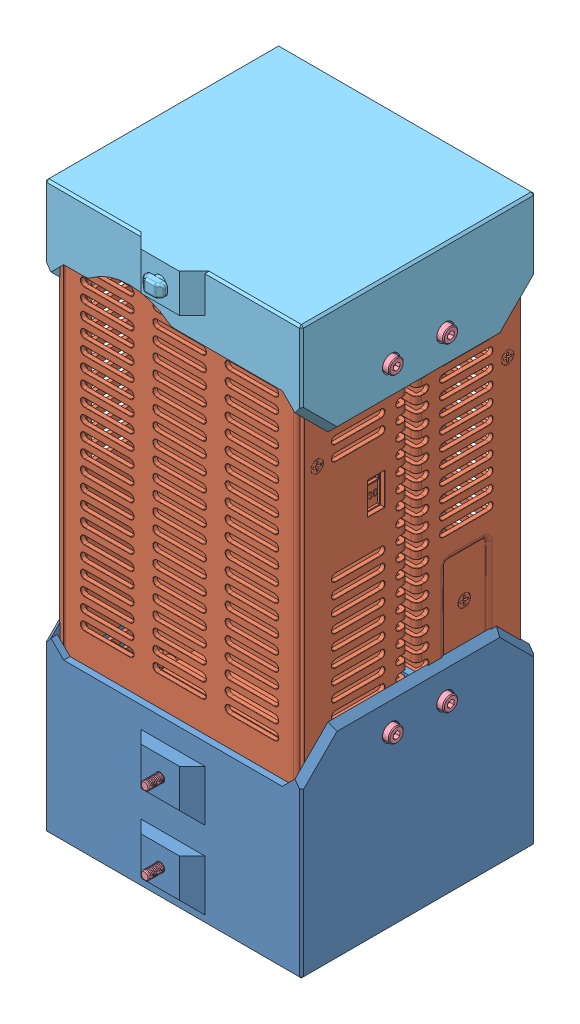
SolidWorks assembly Power Supply Assembly, configuration Default. Lengths in mm.
Overall size (125.7 274 123.3).
17 component instances, 5 part files, 38 mates.
Components (placement in the parent):
- Power Supply Mount-1: Power Supply Mount [Default] at origin size (120.7 96 116)
- Power Supply-4: Power Supply [По умолчанию] at (60.5 155 -56.75) x (-1 0 0) z (0 -1 0) size (115 50.01 215)
- Power Supply-5: Power Supply [По умолчанию] at (60.2 155 -53.25) x (1 0 0) z (0 -1 0) size (115 50.01 215)
- Power Socket-1: Power Socket [Default] at (6.75 -2 -80.75) x (0 0 1) z (0 1 0) size (48.85 59 35)
- socket head cap screw_am-1: socket head cap screw_am [B18.3.1M - 4 x 0.7 x 8 Hex SHCS -- 8SHX] at (-2.5 80 -42.25) size (12 7 7)
- socket head cap screw_am-2: socket head cap screw_am [B18.3.1M - 4 x 0.7 x 8 Hex SHCS -- 8SHX] at (-2.5 80 -67.75) size (12 7 7)
- socket head cap screw_am-3: socket head cap screw_am [B18.3.1M - 4 x 0.7 x 8 Hex SHCS -- 8SHX] at (123.2 80 -42.25) x (-1 0 0) z (0 -0.924225 -0.381849) size (12 7 7)
- socket head cap screw_am-4: socket head cap screw_am [B18.3.1M - 4 x 0.7 x 8 Hex SHCS -- 8SHX] at (123.2 80 -67.75) x (-1 0 0) z (0 -0.924225 -0.381849) size (12 7 7)
- socket head cap screw_am-5: socket head cap screw_am [B18.3.1M - 4 x 0.7 x 8 Hex SHCS -- 8SHX] at (36.25 -6 -100.75) x (0 1 0) z (-0.923728 0 0.383049) size (12 7 7)
- socket head cap screw_am-6: socket head cap screw_am [B18.3.1M - 4 x 0.7 x 8 Hex SHCS -- 8SHX] at (36.25 -6 -60.75) x (0 1 0) z (-0.923728 0 0.383049) size (12 7 7)
- socket head cap screw_am-7: socket head cap screw_am [B18.3.1M - 4 x 0.7 x 12 Hex SHCS -- 12SHX] at (60.35 19 -2.7) x (0 0 1) z (-0.382318 -0.924031 0) size (16 7 7)
- socket head cap screw_am-8: socket head cap screw_am [B18.3.1M - 4 x 0.7 x 12 Hex SHCS -- 12SHX] at (60.35 55.5 -2.7) x (0 0 1) z (-0.923728 -0.383049 0) size (16 7 7)
- Power Supply Upper Mount-1: Power Supply Upper Mount [Default] at (120.7 266 0) x (-1 0 0) z (0 0 1) size (120.7 52 121.05)
- socket head cap screw_am-9: socket head cap screw_am [B18.3.1M - 4 x 0.7 x 8 Hex SHCS -- 8SHX] at (123.2 230 -67.75) x (-1 0 0) z (0 -0.924225 -0.381849) size (12 7 7)
- socket head cap screw_am-10: socket head cap screw_am [B18.3.1M - 4 x 0.7 x 8 Hex SHCS -- 8SHX] at (123.2 230 -42.25) x (-1 0 0) z (0 -0.924225 -0.381849) size (12 7 7)
- socket head cap screw_am-11: socket head cap screw_am [B18.3.1M - 4 x 0.7 x 8 Hex SHCS -- 8SHX] at (-2.5 230 -42.25) size (12 7 7)
- socket head cap screw_am-12: socket head cap screw_am [B18.3.1M - 4 x 0.7 x 8 Hex SHCS -- 8SHX] at (-2.5 230 -67.75) size (12 7 7)
Mates (geometry in assembly coordinates):
- Concentric33: concentric: cylinder of Power Supply Mount-1 through (0 80 -67.75) axis (1 0 0) radius 2.125; cylinder of Power Supply-4 through (118 80 -67.75) axis (-1 0 0) radius 1.3
- Coincident38: coincident: plane of Power Supply Mount-1 through (3 96 0) normal (1 0 0); plane of Power Supply-4 through (3 262.5 -58.75) normal (-1 0 0)
- Parallel1: parallel: plane of Power Supply Mount-1 through (3 189.2392 -56.5) normal (0 0 -1); plane of Power Supply-4 through (60.5 155 -56.75) normal (0 0 1)
- Concentric34: concentric: cylinder of Power Supply Mount-1 through (0 80 -42.25) axis (1 0 0) radius 2.125; cylinder of Power Supply-5 through (2.7 80 -42.25) axis (1 0 0) radius 1.3
- Coincident39: coincident: plane of Power Supply Mount-1 through (117.7 96 0) normal (-1 0 0); plane of Power Supply-5 through (117.7 262.5 -51.25) normal (1 0 0)
- Parallel2: parallel: plane of Power Supply Mount-1 through (117.7 189.2392 -53.5) normal (0 0 1); plane of Power Supply-5 through (60.2 155 -53.25) normal (0 0 -1)
- Concentric37: concentric: cylinder of Power Supply-5 through (2.7 80 -42.25) axis (1 0 0) radius 1.3; cylinder of socket head cap screw_am-1 through (-34.25 80 -42.25) axis (-1 0 0) radius 3.5
- Coincident41: coincident: plane of Power Supply Mount-1 through (1.5 80 -42.25) normal (-1 0 0); plane of socket head cap screw_am-1 through (1.5 83.5 -42.25) normal (1 0 0)
- Concentric38: concentric: cylinder of Power Supply-4 through (118 80 -67.75) axis (-1 0 0) radius 1.3; cylinder of socket head cap screw_am-2 through (-34.25 80 -67.75) axis (-1 0 0) radius 3.5
- Coincident42: coincident: plane of Power Supply Mount-1 through (1.5 80 -67.75) normal (-1 0 0); plane of socket head cap screw_am-2 through (1.5 83.5 -67.75) normal (1 0 0)
- Concentric39: concentric: cylinder of Power Supply-5 through (2.7 80 -42.25) axis (1 0 0) radius 1.3; cylinder of socket head cap screw_am-3 through (154.95 80 -42.25) axis (1 0 0) radius 3.5
- Coincident43: coincident: plane of Power Supply Mount-1 through (119.2 80 -42.25) normal (1 0 0); plane of socket head cap screw_am-3 through (119.2 81.3365 -45.4848) normal (-1 0 0)
- Concentric40: concentric: cylinder of Power Supply-4 through (118 80 -67.75) axis (-1 0 0) radius 1.3; cylinder of socket head cap screw_am-4 through (154.95 80 -67.75) axis (1 0 0) radius 3.5
- Coincident44: coincident: plane of Power Supply Mount-1 through (119.2 80 -67.75) normal (1 0 0); plane of socket head cap screw_am-4 through (119.2 81.3365 -70.9848) normal (-1 0 0)
- Coincident45: coincident: plane of Power Socket-1 through (6.75 -2 -80.75) normal (0 -1 0); plane of socket head cap screw_am-5 through (34.9093 -2 -103.983) normal (0 1 0)
- Coincident46: coincident: plane of Power Socket-1 through (6.75 -2 -80.75) normal (0 -1 0); plane of socket head cap screw_am-6 through (34.9093 -2 -63.983) normal (0 1 0)
- Concentric43: concentric: cylinder of Power Supply Mount-1 through (60.35 19 1.3) axis (0 0 -1) radius 3.65; cylinder of socket head cap screw_am-7 through (60.35 19 -34.45) axis (0 0 -1) radius 3.5
- Coincident47: coincident: plane of Power Supply Mount-1 through (60.35 19 1.3) normal (0 0 -1); plane of socket head cap screw_am-7 through (57.1159 20.3381 1.3) normal (0 0 1)
- Concentric44: concentric: cylinder of Power Supply Mount-1 through (60.35 55.5 1.3) axis (0 0 -1) radius 3.65; cylinder of socket head cap screw_am-8 through (60.35 55.5 -34.45) axis (0 0 -1) radius 3.5
- Coincident48: coincident: plane of Power Supply Mount-1 through (60.35 55.5 1.3) normal (0 0 -1); plane of socket head cap screw_am-8 through (59.0093 58.733 1.3) normal (0 0 1)
- Coincident49: coincident: plane of socket head cap screw_am-5 through (34.9093 -2 -103.983) normal (0 1 0); plane of socket head cap screw_am-6 through (34.9093 -2 -63.983) normal (0 1 0)
- Coincident50: coincident: plane of Power Socket-1 through (6.75 -2 -80.75) normal (0 -1 0); plane of socket head cap screw_am-5 through (34.9093 -2 -103.983) normal (0 1 0)
- Concentric45: concentric: cylinder of Power Socket-1 through (36.25 0 -100.75) axis (0 -1 0) radius 2.25; cylinder of socket head cap screw_am-5 through (36.25 -37.75 -100.75) axis (0 -1 0) radius 3.5
- Concentric46: concentric: cylinder of Power Socket-1 through (36.25 0 -60.75) axis (0 -1 0) radius 2.25; cylinder of socket head cap screw_am-6 through (36.25 -37.75 -60.75) axis (0 -1 0) radius 3.5
- Concentric47: concentric: cylinder of Power Supply Mount-1 through (36.25 59.2539 -60.75) axis (0 -1 0) radius 1.65; cylinder of Power Socket-1 through (36.25 0 -60.75) axis (0 -1 0) radius 2.25
- Concentric48: concentric: cylinder of Power Supply Mount-1 through (36.25 59.2539 -100.75) axis (0 -1 0) radius 1.65; cylinder of Power Socket-1 through (36.25 0 -100.75) axis (0 -1 0) radius 2.25
- Coincident51: coincident: plane of Power Supply Mount-1 through (0 0 0) normal (0 -1 0); plane of Power Socket-1 through (6.75 0 -80.75) normal (0 1 0)
- Concentric49: concentric: cylinder of Power Supply-4 through (118 230 -67.75) axis (-1 0 0) radius 1.3; cylinder of Power Supply Upper Mount-1 through (120.7 230 -67.75) axis (-1 0 0) radius 2.125
- Concentric50: concentric: cylinder of Power Supply-5 through (2.7 230 -42.25) axis (1 0 0) radius 1.3; cylinder of Power Supply Upper Mount-1 through (120.7 230 -42.25) axis (-1 0 0) radius 2.125
- Coincident53: coincident: plane of Power Supply Mount-1 through (120.7 96 0) normal (1 0 0); plane of Power Supply Upper Mount-1 through (120.7 214 0) normal (1 0 0)
- Coincident54: coincident: plane of Power Supply Upper Mount-1 through (119.2 230 -42.25) normal (1 0 0); plane of socket head cap screw_am-10 through (119.2 231.3365 -45.4848) normal (-1 0 0)
- Coincident55: coincident: plane of Power Supply Upper Mount-1 through (119.2 230 -67.75) normal (1 0 0); plane of socket head cap screw_am-9 through (119.2 231.3365 -70.9848) normal (-1 0 0)
- Concentric51: concentric: cylinder of Power Supply Upper Mount-1 through (120.7 230 -42.25) axis (-1 0 0) radius 2.125; cylinder of socket head cap screw_am-10 through (154.95 230 -42.25) axis (1 0 0) radius 3.5
- Concentric52: concentric: cylinder of Power Supply Upper Mount-1 through (120.7 230 -67.75) axis (-1 0 0) radius 2.125; cylinder of socket head cap screw_am-9 through (154.95 230 -67.75) axis (1 0 0) radius 3.5
- Coincident56: coincident: plane of Power Supply Upper Mount-1 through (1.5 230 -42.25) normal (-1 0 0); plane of socket head cap screw_am-11 through (1.5 233.5 -42.25) normal (1 0 0)
- Coincident57: coincident: plane of Power Supply Upper Mount-1 through (1.5 230 -67.75) normal (-1 0 0); plane of socket head cap screw_am-12 through (1.5 233.5 -67.75) normal (1 0 0)
- Concentric53: concentric: cylinder of Power Supply Upper Mount-1 through (120.7 230 -67.75) axis (-1 0 0) radius 2.125; cylinder of socket head cap screw_am-12 through (-34.25 230 -67.75) axis (-1 0 0) radius 3.5
- Concentric54: concentric: cylinder of Power Supply Upper Mount-1 through (120.7 230 -42.25) axis (-1 0 0) radius 2.125; cylinder of socket head cap screw_am-11 through (-34.25 230 -42.25) axis (-1 0 0) radius 3.5
